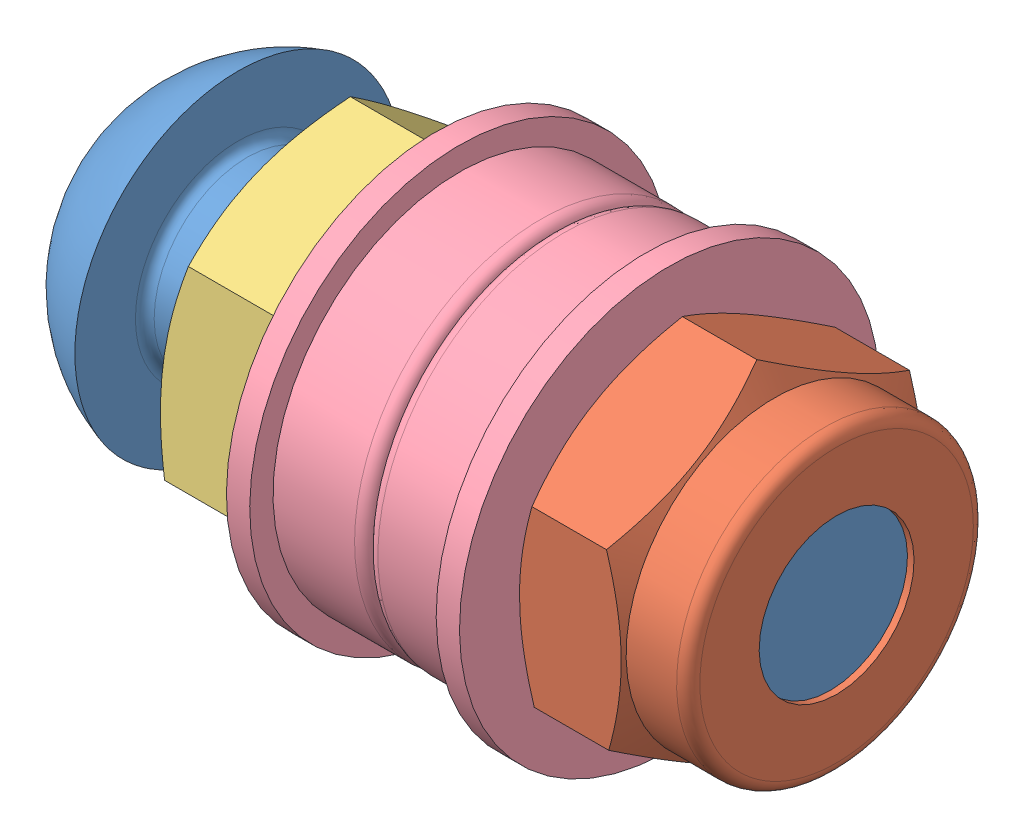
SolidWorks assembly ASM X-Roller Bolt, configuration Standard. Lengths in mm.
Overall size (30.9 25.4 25.4).
5 component instances, 4 part files, 7 mates.
Components (placement in the parent):
- M8X25 Pan Head Screw-1: M8X25 Pan Head Screw [Standard] at origin size (30.62 14.79 14.79)
- M8 Self-locking nut-1: M8 Self-locking nut [Standard] at (27.7325 0 0) x (0 0.488663 0.872473) z (1 0 0) size (15.01 13 7.18)
- M8 nut-1: M8 nut [Standard] at (7.4 0 0) x (0 0.613039 0.790053) z (-1 0 0) size (15.01 13 5.5)
- F688 pillow-1: F688 pillow [Standard] at (22.9 0 0) x (0 0.424513 0.905422) z (0 -0.905422 0.424513) size (18 5 18)
- F688 pillow-2: F688 pillow [Standard] at (12.9 0 0) x (0 0.751639 -0.659574) z (0 -0.659574 -0.751639) size (18 5 18)
Mates (geometry in assembly coordinates):
- Konzentrisch35: concentric aligned: cylinder of M8X25 Pan Head Screw-1 through (14.4 0 0) axis (-1 0 0) radius 4; cylinder of M8 nut-1 through (14.2 0 0) axis (-1 0 0) radius 3.3235
- Konzentrisch36: concentric aligned: cylinder of M8X25 Pan Head Screw-1 through (14.4 0 0) axis (-1 0 0) radius 4; cylinder of F688 pillow-2 through (17.9 0 0) axis (-1 0 0) radius 4
- Konzentrisch37: concentric anti-aligned: cylinder of M8X25 Pan Head Screw-1 through (14.4 0 0) axis (-1 0 0) radius 4; cylinder of F688 pillow-1 through (17.9 0 0) axis (1 0 0) radius 4
- Konzentrisch38: concentric anti-aligned: cylinder of M8X25 Pan Head Screw-1 through (14.4 0 0) axis (-1 0 0) radius 4; cylinder of M8 Self-locking nut-1 through (22.5825 0 0) axis (1 0 0) radius 3.3235
- Deckungsgleich34: coincident anti-aligned: plane of M8 Self-locking nut-1 through (22.9 0.1695 -12.9989) normal (-1 0 0); plane of F688 pillow-1 through (22.9 0 0) normal (1 0 0)
- Deckungsgleich32: coincident anti-aligned: plane of M8 nut-1 through (12.9 -6.1931 -10.6321) normal (1 0 0); plane of F688 pillow-2 through (12.9 0 0) normal (-1 0 0)
- Deckungsgleich33: coincident anti-aligned: plane of F688 pillow-1 through (17.9 0 0) normal (-1 0 0); plane of F688 pillow-2 through (17.9 0 0) normal (1 0 0)
